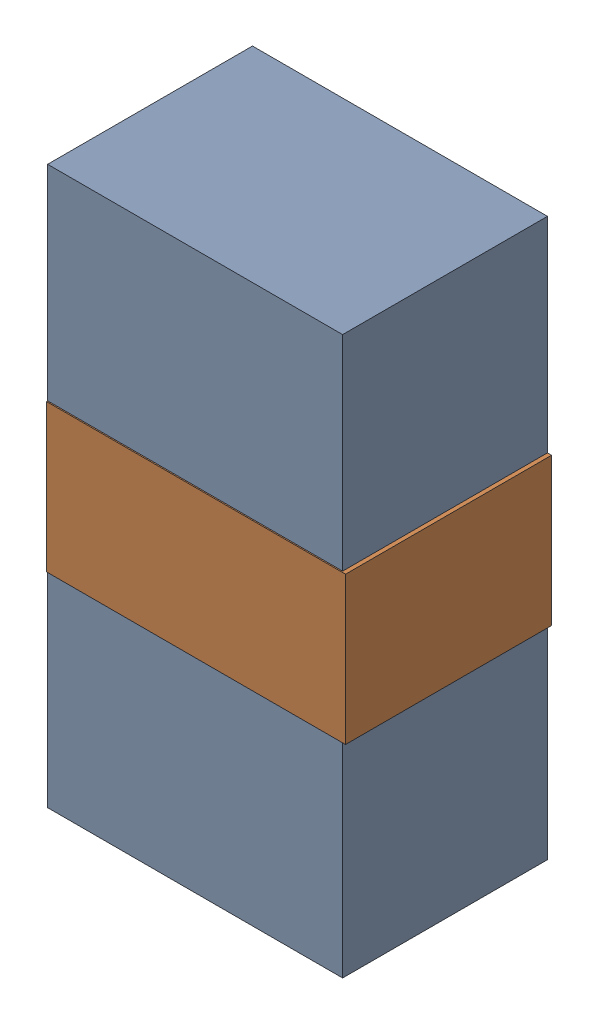
SolidWorks assembly LED2_Motor_11Kanaloa_v2.0.0_Motor, configuration Default. Lengths in mm.
Overall size (1.83 3.4 1.26).
4 component instances, 2 part files, 0 mates.
Components (placement in the parent):
- 334788016-1: 334788016 [Default] at (128.0035 173.482 0) size (1.8 3.4 1.25)
  - Extruded_12-1: Extruded_12 [Default] at origin size (1.8 3.4 1.25)
- 334787760-1: 334787760 [Default] at (128.016 173.482 0) size (1.83 0.9 1.26)
  - Extruded_13-1: Extruded_13 [Default] at origin size (1.83 0.9 1.26)
